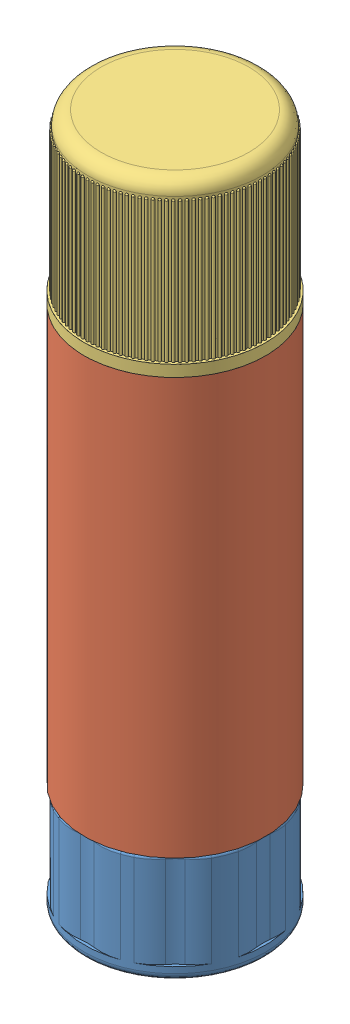
SolidWorks assembly Glue Stick, configuration Default. Lengths in mm.
Overall size (27 103 27).
3 component instances, 3 part files, 4 mates.
Components (placement in the parent):
- Glue Stick Base-1: Glue Stick Base [Default] at origin size (27 69.74 27)
- Glue Stick Body-1: Glue Stick Body [Default] at (0 16 0) size (27 80 27)
- Glue Stick Cap-1: Glue Stick Cap [Default] at (0 78 0) size (27 25 27)
Mates (geometry in assembly coordinates):
- Coincident1: coincident: plane of Glue Stick Base-1 through (0 16 0) normal (0 1 0); plane of Glue Stick Body-1 through (11.3 16 0) normal (0 -1 0)
- Concentric1: concentric: cylinder of Glue Stick Base-1 through (0 21 0) axis (0 -1 0) radius 11.3; cylinder of Glue Stick Body-1 through (0 68.2625 0) axis (0 1 0) radius 11.3
- Concentric2: concentric: cylinder of Glue Stick Body-1 through (0 68.2625 0) axis (0 1 0) radius 12.5; cylinder of Glue Stick Cap-1 through (0 79.7 0) axis (0 1 0) radius 12.5
- Coincident2: coincident: plane of Glue Stick Body-1 through (13.5 78 0) normal (0 1 0); plane of Glue Stick Cap-1 through (0 78 0) normal (0 -1 0)
